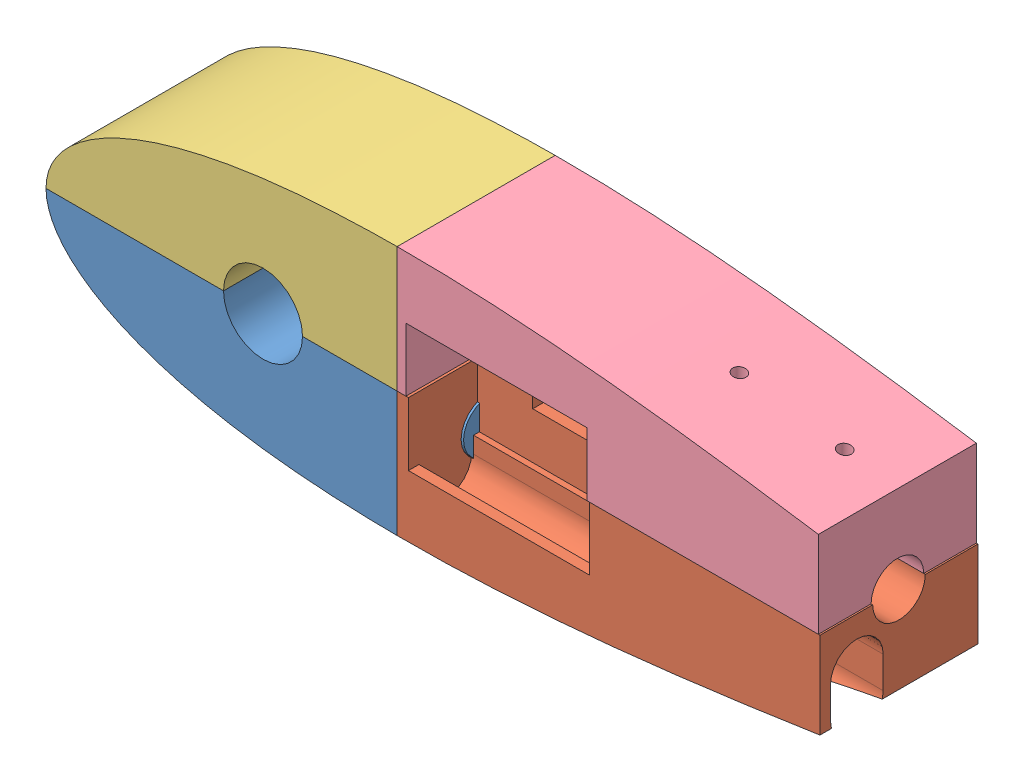
SolidWorks assembly Main Joint with holes for wire december 9, configuration Default. Lengths in mm.
Overall size (376.7 120.73 76.2).
4 component instances, 4 part files, 9 mates.
Components (placement in the parent):
- H1S1-1: H1S1 [Default] at (-190.1363 27.5484 88.147) size (176.06 73.05 76.2)
- H1S2-1: H1S2 [Default] at (-189.3276 27.5264 88.1287) size (277.53 60.37 76.2)
- H2S1-1: H2S1 [Default] at (-189.2402 27.9053 12.6339) x (1 0 0) z (0 0 -1) size (176.06 60.77 76.2)
- H2S2-1: H2S2 [Default] at (-189.3276 27.9036 12.6339) x (1 0 0) z (0 0 -1) size (273.65 60.4 76.2)
Mates (geometry in assembly coordinates):
- Coincident1: coincident anti-aligned: plane of H1S1-1 through (-19.9096 27.5484 88.147) normal (1 0 0); plane of H1S2-1 through (-19.9096 27.5264 88.1287) normal (-1 0 0)
- Concentric1: concentric anti-aligned: circle of H1S1-1; circle of H1S2-1
- Parallel1: parallel aligned: line of H1S1-1 through (-19.9096 27.9053 12.6339) axis (0 0 1); line of H1S2-1 through (-19.9096 27.9036 12.6339) axis (0 0 1)
- Coincident7: coincident anti-aligned: plane of H1S1-1 through (284.8904 27.9053 114.2339) normal (0 1 0); plane of H2S1-1 through (284.8904 27.9053 -12.7661) normal (0 -1 0)
- Coincident8: coincident aligned: axis of H1S1-1 through (-36.8402 40.6053 50.7339) axis (0 -1 0); axis of H2S1-1 through (-36.8402 40.6053 50.7339) axis (0 -1 0)
- Parallel2: parallel anti-aligned: line of H1S1-1 through (-189.2402 27.9053 47.3049) axis (0 0 -1); line of H2S1-1 through (-189.2402 27.9053 12.6339) axis (0 0 1)
- Coincident10: coincident anti-aligned: plane of H1S2-1 through (285.5761 27.9036 114.2339) normal (0 1 0); plane of H2S2-1 through (284.8031 27.9036 -12.7661) normal (0 -1 0)
- Coincident15: coincident anti-aligned: line of H1S2-1 through (72.8941 27.9036 88.8339) axis (1 0 0); line of H2S2-1 through (183.2031 27.9036 88.8339) axis (-1 0 0)
- Coincident17: coincident anti-aligned: plane of H2S1-1 through (-19.9096 27.9053 12.6339) normal (1 0 0); plane of H2S2-1 through (-19.9096 27.9036 12.6339) normal (-1 0 0)
